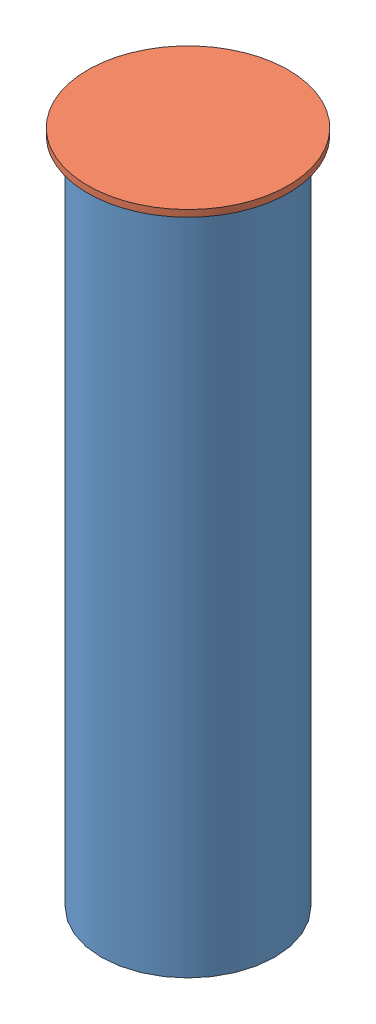
SolidWorks assembly Hülle, configuration Standard. Lengths in mm.
Overall size (71.97 202 71.97).
2 component instances, 2 part files, 2 mates.
Components (placement in the parent):
- Rohr-1: Rohr [Standard] at (-6.2133 -99.6117 200) size (52 200 52)
- Deckel-1: Deckel [Standard] at (-6.2133 102.3883 200) x (-0.837169 0 -0.546944) z (-0.546944 0 0.837169) size (52 12 52)
Mates (geometry in assembly coordinates):
- Deckungsgleich1: coincident anti-aligned: plane of Rohr-1 through (-6.2133 100.3883 200) normal (0 1 0); plane of Deckel-1 through (-6.2133 100.3883 200) normal (0 -1 0)
- Konzentrisch1: concentric anti-aligned: cylinder of Rohr-1 through (-6.2133 100.3883 200) axis (0 -1 0) radius 25; cylinder of Deckel-1 through (-6.2133 90.3883 200) axis (0 1 0) radius 25
